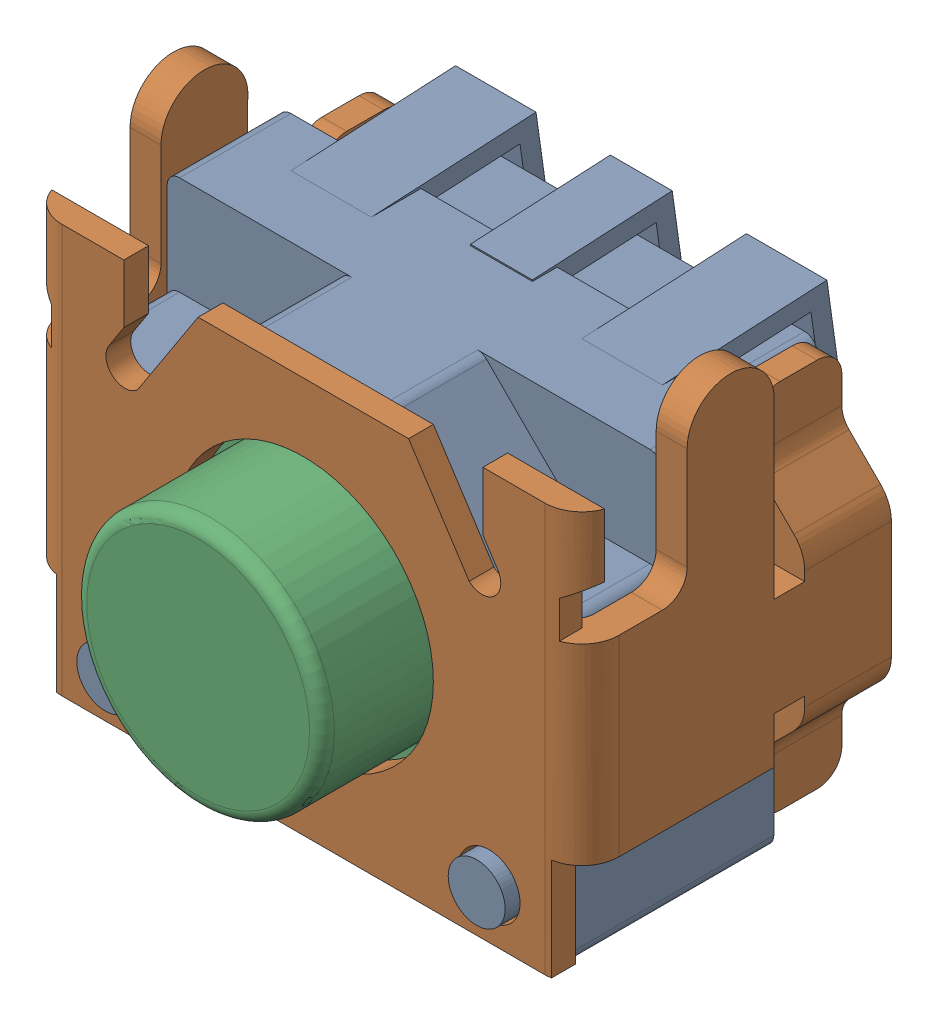
SolidWorks assembly TL3340AF160QG, configuration Default. Lengths in mm.
Overall size (4.5 3.76 3.67).
3 component instances, 3 part files, 0 mates.
Components (placement in the parent):
- 2000862_Housing-1: 2000862_Housing [Default] x (-1 0 0) z (0 0 1) size (4 3.27 2.92)
- 2000862_Bracket-1: 2000862_Bracket [Default] at (0 0 2.35) x (-1 0 0) z (0 0 1) size (4.5 3.76 2.5)
- 2000862_Actuator-1: 2000862_Actuator [Default] at (0 0 1.85) x (-1 0 0) z (0 1 0) size (2.5 1.95 2.5)
